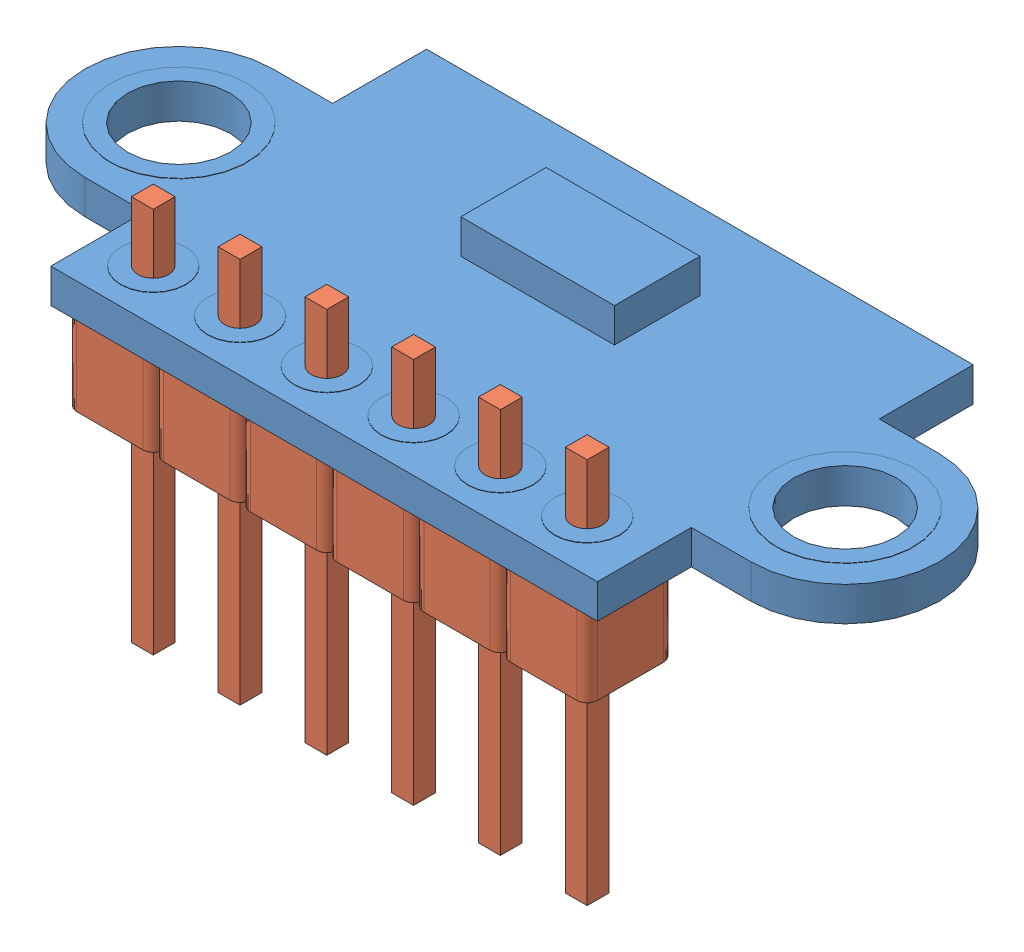
SolidWorks assembly vl53l0x, configuration Default. Lengths in mm.
Overall size (25 11.3 11).
7 component instances, 2 part files, 4 mates.
Components (placement in the parent):
- vl53l0x_PCB-1: vl53l0x_PCB [Default] at origin size (25 3 11)
- pin_header-1: pin_header [Default] at (-6.5 -2.54 4) size (2.54 11.3 2.54)
- pin_header-2: pin_header [Default] at (-3.96 -2.54 4) size (2.54 11.3 2.54)
- pin_header-3: pin_header [Default] at (-1.42 -2.54 4) size (2.54 11.3 2.54)
- pin_header-4: pin_header [Default] at (1.12 -2.54 4) size (2.54 11.3 2.54)
- pin_header-5: pin_header [Default] at (3.66 -2.54 4) size (2.54 11.3 2.54)
- pin_header-6: pin_header [Default] at (6.2 -2.54 4) size (2.54 11.3 2.54)
Mates (geometry in assembly coordinates):
- Совпадение1: coincident: plane of vl53l0x_PCB-1 through (-9.75 0 0) normal (0 -1 0); plane of pin_header-1 through (-7.47 0 4.97) normal (0 1 0)
- Расстояние1: distance = 0.23 mm: plane of pin_header-1 through (-7.77 0 4.97) normal (-1 0 0); plane of vl53l0x_PCB-1 through (-8 1 5.5) normal (-1 0 0)
- Расстояние2: distance = 0.23 mm: plane of pin_header-1 through (-5.53 0 5.27) normal (0 0 1); plane of vl53l0x_PCB-1 through (8 1 5.5) normal (0 0 1)
- Совпадение6: coordinate: point of vl53l0x_PCB-1; point of assembly
